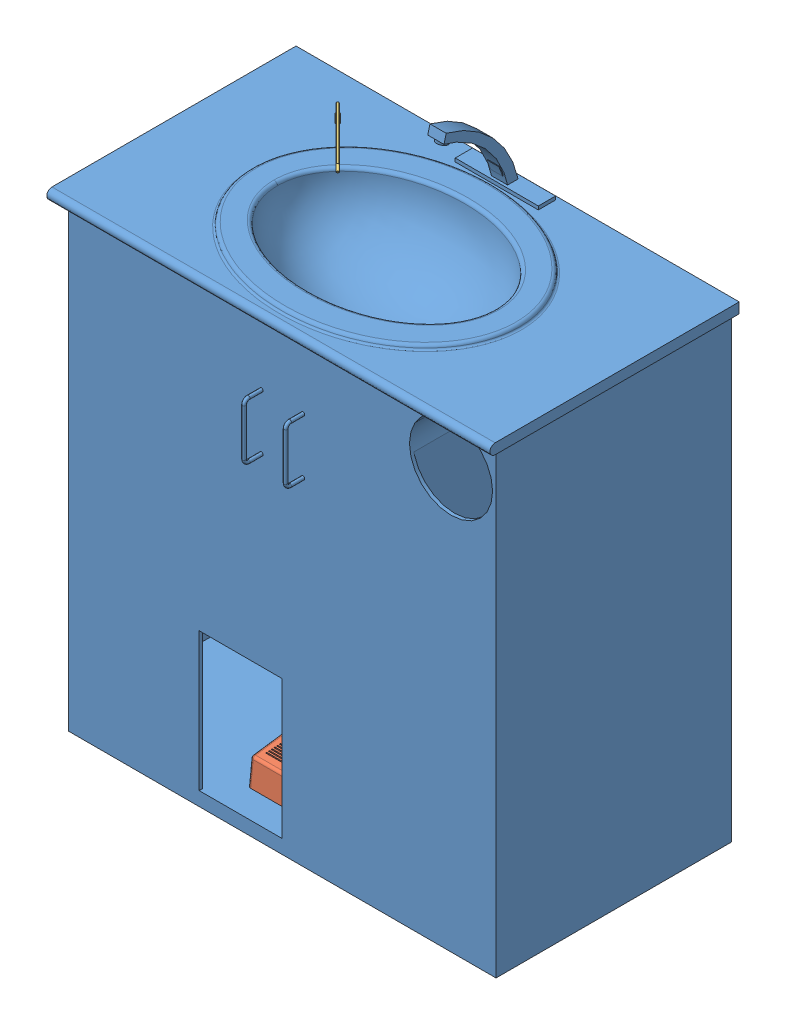
SolidWorks assembly SinkwSoap, configuration Default. Lengths in mm.
Overall size (812.8 1010.12 517.52).
3 component instances, 3 part files, 4 mates.
Components (placement in the parent):
- Sink_new-1: Sink_new [No Side Overhangs] at origin size (812.8 1010.12 517.52)
- Soap Foot Pump-1: Soap Foot Pump [Default] at (293.05 25.4 -76.2) size (89.29 56.68 113.79)
- Soap Pump Head-1: Soap Pump Head [Default] at (160.6433 865.124 -372.9915) x (0.707107 0 -0.707107) z (0.707107 0 0.707107) size (7 94.57 237.72)
Mates (geometry in assembly coordinates):
- Coincident3: coincident anti-aligned: plane of Sink_new-1 through (254 25.4 -431.8) normal (0 1 0); plane of Soap Foot Pump-1 through (293.05 25.4 -76.2) normal (0 -1 0)
- Width1: width anti-aligned: plane of Sink_new-1 through (254 279.4 -431.8) normal (1 0 0); plane of Soap Foot Pump-1 through (406.4 279.4 -431.8) normal (-1 0 0); plane of Sink_new-1 through (375.2 25.4 -189.9899) normal (0.996262 0.052336 0.068729); plane of Soap Foot Pump-1 through (293.05 25.4 -76.2) normal (-0.996262 0.052336 0.068729)
- Coincident8: coincident anti-aligned: plane of Sink_new-1 through (0 865.124 0) normal (0 1 0); plane of Soap Pump Head-1 through (160.6433 865.124 -372.9915) normal (0 -1 0)
- Distance5: distance = 169.5567 mm: cylinder of Soap Pump Head-1 through (160.6433 880.124 -372.9915) axis (0 -1 0) radius 3.5; plane of Sink_new-1 through (330.2 871.474 -450.7006) normal (-1 0 0)
